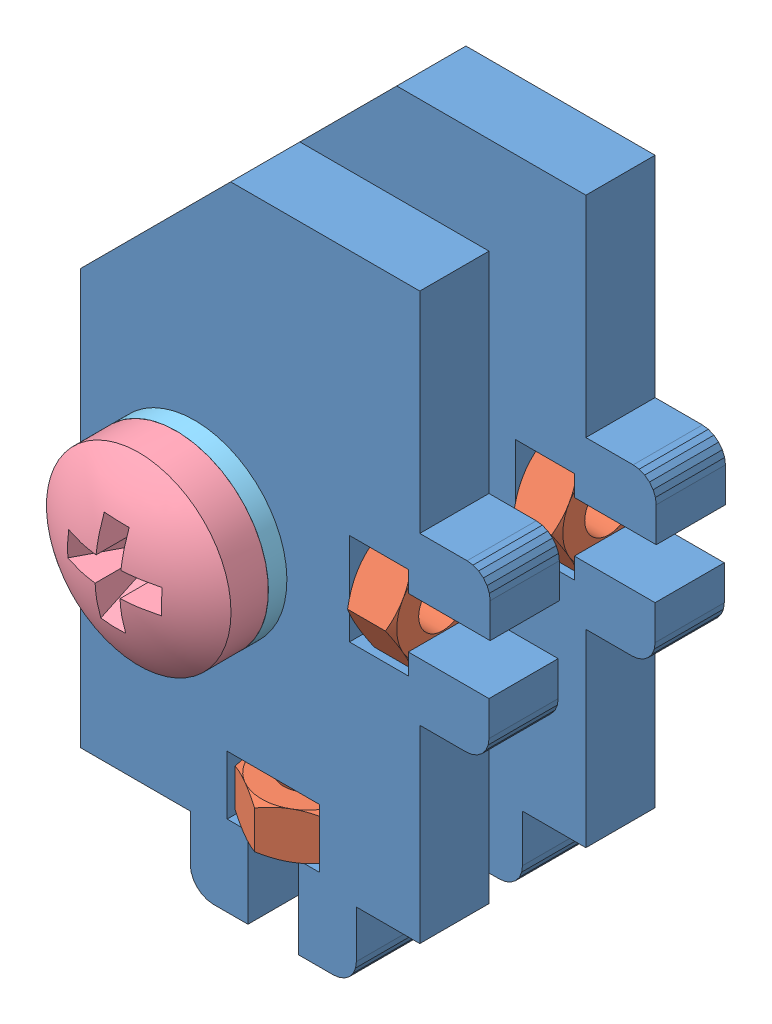
SolidWorks assembly Assembly Y-Idler, configuration Valor predeterminado. Lengths in mm.
Overall size (40.86 55.1 36.01).
13 component instances, 6 part files, 13 mates.
Components (placement in the parent):
- Assembly Y-Idler side-1: Assembly Y-Idler side [Valor predeterminado] at (-12.5134 -1.2532 55.1) size (35.5 55.1 11.55)
  - Y-Idler-1: Y-Idler [Valor predeterminado] at (-45.7812 -37.3339 -3) size (35.5 55.1 6)
  - Nut DIN 934 - M5-1: Nut DIN 934 - M5 [Valor predeterminado] at (0 -20.6 0) x (0 -1 0) z (-0.866025 0 -0.5) size (4 8 9.24)
  - Nut DIN 934 - M5-2: Nut DIN 934 - M5 [Valor predeterminado] at (9.7 0 0) x (1 0 0) z (0 -0.866025 0.5) size (4 8 9.24)
- Assembly Y-Idler side-2: Assembly Y-Idler side [Valor predeterminado] at (-12.5134 -1.2532 69.5) size (35.5 55.1 11.55)
  - Y-Idler-1: Y-Idler [Valor predeterminado] at (-45.7812 -37.3339 -3) size (35.5 55.1 6)
  - Nut DIN 934 - M5-1: Nut DIN 934 - M5 [Valor predeterminado] at (0 -20.6 0) x (0 -1 0) z (-0.866025 0 -0.5) size (4 8 9.24)
  - Nut DIN 934 - M5-2: Nut DIN 934 - M5 [Valor predeterminado] at (9.7 0 0) x (1 0 0) z (0 -0.866025 0.5) size (4 8 9.24)
- Radial ball bearing DIN 625 - 608-1: Radial ball bearing DIN 625 - 608 [Valor predeterminado] at (-19.3361 -3.3132 62.3) x (0 0 -1) z (0.549427 0.835542 0) size (7 22 22)
- Screw DIN 7985 - M8 x 30 --- 30N-1: Screw DIN 7985 - M8 x 30 --- 30N [Valor predeterminado] at (-19.3361 -3.3132 80.1) x (0 0 1) z (-0.999331 0.036572 0) size (35.91 16 16)
- Washer DIN 125A - M8-1: Washer DIN 125A - M8 [Valor predeterminado] at (-19.3361 -3.3132 72.5) x (0 0 1) z (-0.960959 0.276691 0) size (1.6 16 16)
- Nut DIN 934 - M8-1: Nut DIN 934 - M8 [Valor predeterminado] at (-19.3361 -3.3132 47.25) x (0 0 1) z (-0.991432 -0.130626 0) size (6.5 13 15.01)
- Washer DIN 125A - M8-2: Washer DIN 125A - M8 [Valor predeterminado] at (-19.3361 -3.3132 50.5) x (0 0 1) z (-0.960959 0.276691 0) size (1.6 16 16)
Mates (geometry in assembly coordinates):
- Concêntrico2: concentric: cylinder of Assembly Y-Idler side-1/Y-Idler-1 through (-19.3361 -3.3132 58.1) axis (0 0 -1) radius 4; cylinder of ? through (-19.3361 -3.3132 106.831) axis (0 0 -1) radius 4
- Coincidente1: coincident: plane of Assembly Y-Idler side-1/Y-Idler-1 through (0.1866 24.1468 58.1) normal (0 1 0); plane of ? through (0.1866 24.1468 106.831) normal (0 1 0)
- Concêntrico3: concentric: cylinder of Assembly Y-Idler side-1/Y-Idler-1 through (-19.3361 -3.3132 58.1) axis (0 0 -1) radius 4; cylinder of ? through (-19.3361 -3.3132 93.7359) axis (0 0 -1) radius 4
- Concêntrico4: concentric: cylinder of ? through (-19.3361 -3.3132 114.431) axis (0 0 1) radius 4; cylinder of ? through (-19.3361 -3.3132 108.431) axis (0 0 -1) radius 4.2
- Coincidente4: coincident: plane of ? through (-19.1898 0.6842 108.431) normal (0 0 -1); plane of ? through (-19.3361 -3.3132 108.431) normal (0 0 1)
- Concêntrico5: concentric: cylinder of ? through (-19.3361 -3.3132 106.831) axis (0 0 -1) radius 4; cylinder of ? through (-19.3361 -3.3132 114.431) axis (0 0 1) radius 4
- Coincidente5: coincident: plane of ? through (-58.2945 -38.5871 106.831) normal (0 0 1); plane of ? through (-19.3361 -3.3132 106.831) normal (0 0 -1)
- Concêntrico6: concentric: cylinder of ? through (-19.3361 -3.3132 114.431) axis (0 0 1) radius 4; cylinder of Washer DIN 125A - M8-2 through (-19.3361 -3.3132 52.1) axis (0 0 -1) radius 4.2
- Coincidente6: coincident: plane of assembly; plane of assembly; plane of Assembly Y-Idler side-1/Y-Idler-1 through (-58.2945 -38.5871 52.1) normal (0 0 -1); plane of Washer DIN 125A - M8-2 through (-19.3361 -3.3132 52.1) normal (0 0 1)
- Concêntrico7: concentric: cylinder of ? through (-19.3361 -3.3132 114.431) axis (0 0 1) radius 4; cylinder of Nut DIN 934 - M8-1 through (-19.3361 -3.3132 50.5) axis (0 0 -1) radius 3.4
- Coincidente8: coincident: plane of assembly; plane of assembly; plane of Nut DIN 934 - M8-1 through (-11.8948 -2.3327 50.5) normal (0 0 1); plane of Washer DIN 125A - M8-2 through (-19.3361 -3.3132 50.5) normal (0 0 -1)
- Distância1: distance = 14.4 mm: plane of assembly; plane of assembly; plane of Assembly Y-Idler side-1 through (-12.5134 -1.2532 55.1) normal (0 0 1); plane of Assembly Y-Idler side-2 through (-12.5134 -1.2532 69.5) normal (0 0 1)
- Simétrico1: symmetric: plane of assembly; plane of assembly; plane of Assembly Y-Idler side-1 through (-12.5134 -1.2532 55.1) normal (0 0 1); plane of Assembly Y-Idler side-2 through (-12.5134 -1.2532 69.5) normal (0 0 1); plane of Radial ball bearing DIN 625 - 608-1 through (-19.3361 -3.3132 62.3) normal (0 0 -1)
